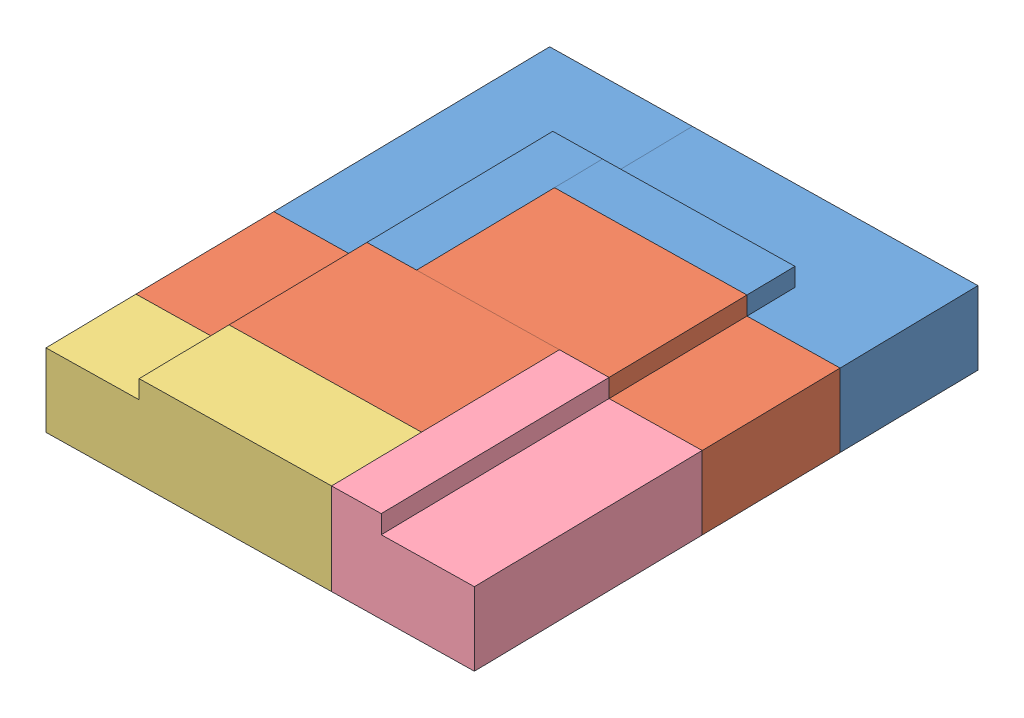
SolidWorks assembly Bottom-top-cut, configuration Default. Lengths in mm.
Overall size (352.28 75 425.96).
6 component instances, 4 part files, 10 mates.
Components (placement in the parent):
- Brick-Sharp-BackLeftCut-1: Brick-Sharp-BackLeftCut [Default] at (-84.1473 -135.3254 -303.3983) x (-0.999848 0 0.017452) z (-0.017452 0 -0.999848) size (230 75 115)
- Brick-Sharp-BackCut-1: Brick-Sharp-BackCut [Default] at (-82.1403 -135.3254 -188.4158) x (-0.999848 0 0.017452) z (-0.017452 0 -0.999848) size (230 75 115)
- Brick-Sharp-BackLeftCut-2: Brick-Sharp-BackLeftCut [Default] at (-255.6175 -135.3254 -242.8965) x (0.017452 0 0.999848) z (-0.999848 0 0.017452) size (230 75 115)
- Brick-Sharp-BackCut-2: Brick-Sharp-BackCut [Default] at (-195.1157 -135.3254 -71.4263) x (0.999848 0 -0.017452) z (0.017452 0 0.999848) size (230 75 115)
- Brick-Sharp-BackCut-short-1: Brick-Sharp-BackCut-short [Default] at (-193.4577 -135.3254 23.5592) x (0.999848 0 -0.017452) z (0.017452 0 0.999848) size (230 75 75)
- Brick-Sharp-SideCut-short-1: Brick-Sharp-SideCut-short [Default] at (-21.9875 -135.3254 -36.9425) x (0.017452 0 0.999848) z (-0.999848 0 0.017452) size (190 75 115)
Mates (geometry in assembly coordinates):
- Coincident1: coincident anti-aligned: plane of Brick-Sharp-BackLeftCut-1 through (31.8387 -97.8254 -247.9141) normal (0.017452 0 0.999848); plane of Brick-Sharp-BackCut-1 through (31.8387 -97.8254 -247.9141) normal (-0.017452 0 -0.999848)
- Coincident2: coincident aligned: line of Brick-Sharp-BackLeftCut-1 through (31.8387 -112.8254 -247.9141) axis (-0.017452 0 -0.999848); line of Brick-Sharp-BackCut-1 through (33.8457 -112.8254 -132.9316) axis (-0.017452 0 -0.999848)
- Coincident10: coincident anti-aligned: plane of Brick-Sharp-BackCut-1 through (-196.1192 -97.8254 -128.9175) normal (-0.999848 0 0.017452); plane of Brick-Sharp-BackLeftCut-2 through (-200.1333 -97.8254 -358.8825) normal (0.999848 0 -0.017452)
- Coincident11: coincident aligned: line of Brick-Sharp-BackLeftCut-1 through (29.8317 -172.8254 -362.8966) axis (-0.999848 0 0.017452); line of Brick-Sharp-BackLeftCut-2 through (-200.1333 -172.8254 -358.8825) axis (-0.999848 0 0.017452)
- Coincident12: coincident anti-aligned: plane of Brick-Sharp-BackLeftCut-2 through (-196.1192 -97.8254 -128.9175) normal (0.017452 0 0.999848); plane of Brick-Sharp-BackCut-2 through (-311.1017 -97.8254 -126.9105) normal (-0.017452 0 -0.999848)
- Coincident13: coincident aligned: line of Brick-Sharp-BackLeftCut-2 through (-315.1158 -172.8254 -356.8755) axis (0.017452 0 0.999848); line of Brick-Sharp-BackCut-2 through (-311.1017 -172.8254 -126.9105) axis (0.017452 0 0.999848)
- Coincident19: coincident anti-aligned: plane of Brick-Sharp-BackCut-1 through (33.8457 -97.8254 -132.9316) normal (0.017452 0 0.999848); plane of Brick-Sharp-SideCut-short-1 through (33.8457 -97.8254 -132.9316) normal (-0.017452 0 -0.999848)
- Coincident20: coincident aligned: line of Brick-Sharp-BackCut-1 through (33.8457 -172.8254 -132.9316) axis (-0.017452 0 -0.999848); line of Brick-Sharp-SideCut-short-1 through (37.1617 -172.8254 57.0395) axis (-0.017452 0 -0.999848)
- Coincident21: coincident anti-aligned: plane of Brick-Sharp-BackCut-2 through (-309.0947 -97.8254 -11.928) normal (0.017452 0 0.999848); plane of Brick-Sharp-BackCut-short-1 through (-309.0947 -97.8254 -11.928) normal (-0.017452 0 -0.999848)
- Coincident22: coincident aligned: line of Brick-Sharp-BackCut-2 through (-311.1017 -172.8254 -126.9105) axis (0.017452 0 0.999848); line of Brick-Sharp-BackCut-short-1 through (-309.0947 -172.8254 -11.928) axis (0.017452 0 0.999848)
